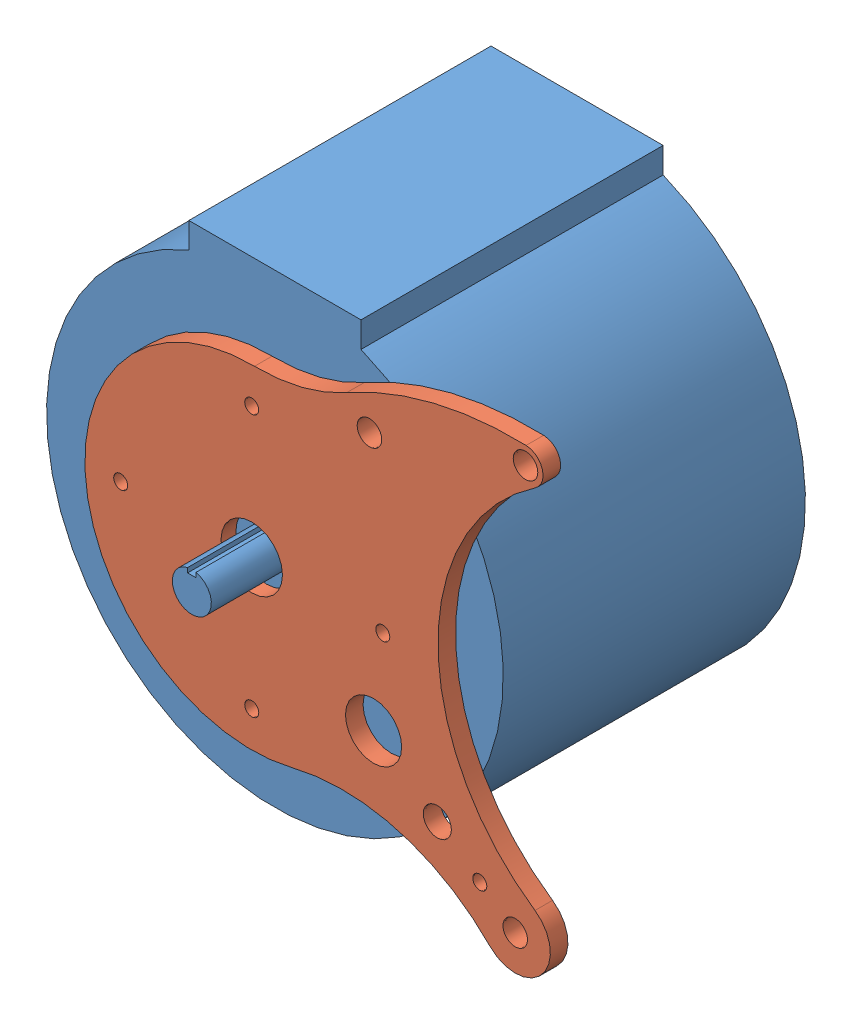
SolidWorks assembly MotorMountAssy, configuration Default. Lengths in mm.
Overall size (300 265 219.3).
2 component instances, 2 part files, 4 mates.
Components (placement in the parent):
- ME1616-1: ME1616 [Default] at origin size (260 265 219.3)
- MotorMount-1: MotorMount [Default] at (0 0 3.2) size (265 263.39 10)
Mates (geometry in assembly coordinates):
- InPlace1: in place: plane of ME1616-1 through (0 0 3.2) normal (0 0 1); plane of MotorMount-1 through (0 0 3.2) normal (0 0 1); moOrthogonalPlaneRef_w of ME1616-1 through (0 0 3.2) normal (0 0 1); plane of MotorMount-1 through (0 0 3.2) normal (0 1 0); plane of ME1616-1 through (0 0 3.2) normal (0 0 1); plane of MotorMount-1 through (0 0 3.2) normal (1 0 0); plane of ME1616-1 through (0 0 3.2) normal (0 0 1); unknown of MotorMount-1
- Coincident1: coincident: plane of ME1616-1; plane of MotorMount-1
- Coincident2: coincident: moOrthogonalPlaneRef_w of ME1616-1 through (0 0 3.2) normal (0 1 0); plane of MotorMount-1 through (0 0 3.2) normal (0 1 0)
- Coincident3: coincident: moOrthogonalPlaneRef_w of ME1616-1 through (0 0 3.2) normal (-1 0 0); plane of MotorMount-1 through (0 0 3.2) normal (1 0 0)
